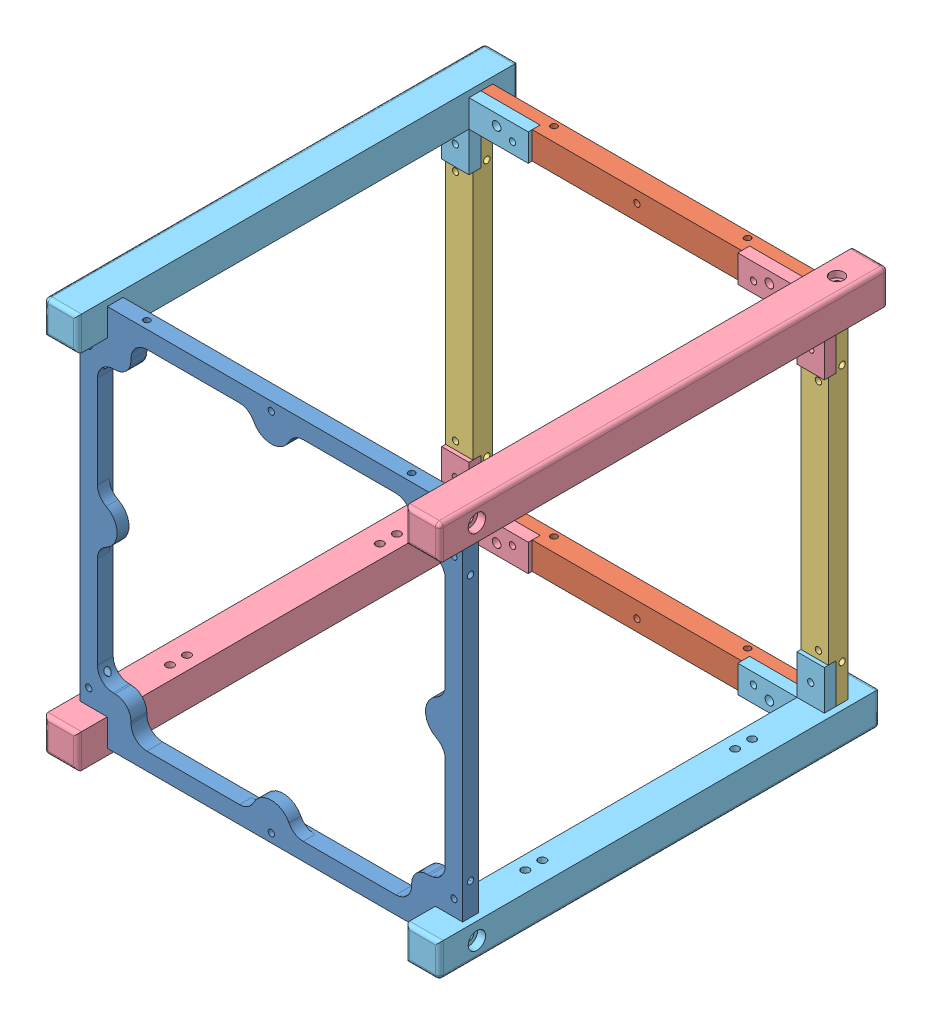
SolidWorks assembly B3_main, configuration ﾃﾞﾌｫﾙﾄ. Lengths in mm.
Overall size (100 100 113.5).
11 component instances, 6 part files, 32 mates.
Components (placement in the parent):
- B3_flame1-1: B3_flame1 [Default] at origin size (96.8 96.8 4)
- B3_flame2-1: B3_flame2 [Default] at (76.5 -8.5 -87.5) x (-1 0 0) z (0 1 0) size (83 5 6.9)
- B3_flame3-1: B3_flame3 [Default] at (100 -8.5 -85.4016) x (-1 0 0) z (0 1 0) size (6.9 5 83)
- B3_flame5-1: B3_flame5 [Default] at (100 -8.5 11.5) x (-1 0 0) z (0 1 0) size (23.5 113.5 18.5)
- B3_flame6-1: B3_flame6 [Default] at (91.5 -91.5 11.5) x (1 0 0) z (0 -1 0) size (23.5 111.5 18.5)
- B3_flame5-2: B3_flame5 [Default] at (0 -91.5 11.5) x (1 0 0) z (0 -1 0) size (23.5 113.5 18.5)
- B3_flame6-2: B3_flame6 [Default] at (8.5 -8.5 11.5) x (-1 0 0) z (0 1 0) size (23.5 111.5 18.5)
- B3_flame2-2: B3_flame2 [Default] at (23.5 -91.5 -87.5) x (1 0 0) z (0 -1 0) size (83 5 6.9)
- B3_flame3-2: B3_flame3 [Default] at (0 -91.5 -85.4016) x (1 0 0) z (0 -1 0) size (6.9 5 83)
- B3_flame7-1: B3_flame7 [Default] at (4.25 -91.5 -96.25) x (1 0 0) z (0 -1 0) size (5.5 8.5 5)
- B3_flame7-2: B3_flame7 [Default] at (95.75 -8.5 -96.25) x (-1 0 0) z (0 1 0) size (5.5 8.5 5)
Mates (geometry in assembly coordinates):
- Concentric5: concentric anti-aligned: cylinder of B3_flame3-1 through (94.95 -86.5 -93.5) axis (0 0 -1) radius 1.2; cylinder of B3_flame6-1 through (94.95 -86.5 -87.5) axis (0 0 1) radius 0.8
- Concentric6: concentric anti-aligned: cylinder of B3_flame3-1 through (94.95 -13.5 -93.5) axis (0 0 -1) radius 1.2; cylinder of B3_flame5-1 through (94.95 -13.5 -87.5) axis (0 0 1) radius 0.8
- Concentric7: concentric anti-aligned: cylinder of B3_flame6-2 through (5.05 -13.5 -87.5) axis (0 0 1) radius 0.8; cylinder of B3_flame3-2 through (5.05 -13.5 -93.5) axis (0 0 -1) radius 1.2
- Concentric9: concentric anti-aligned: cylinder of B3_flame2-1 through (15.5 -4.3 -93.5) axis (0 0 -1) radius 0.8; cylinder of B3_flame6-2 through (15.5 -4.3 -87.5) axis (0 0 1) radius 1.1
- Concentric10: concentric anti-aligned: cylinder of B3_flame2-1 through (84.5 -4.3 -93.5) axis (0 0 -1) radius 0.8; cylinder of B3_flame5-1 through (84.5 -4.3 -87.5) axis (0 0 1) radius 1.1
- Concentric11: concentric anti-aligned: cylinder of B3_flame5-2 through (15.5 -95.7 -87.5) axis (0 0 1) radius 1.1; cylinder of B3_flame2-2 through (15.5 -95.7 -93.5) axis (0 0 -1) radius 0.8
- Coincident1: coincident anti-aligned: plane of B3_flame2-1 through (91.5 0 -90.5) normal (0 0 1); plane of B3_flame5-1 through (76.5 0 -90.5) normal (0 0 -1)
- Coincident2: coincident anti-aligned: plane of B3_flame6-2 through (8.5 -18.5 -90.5) normal (0 0 -1); plane of B3_flame3-2 through (-1.5 -8.5 -90.5) normal (0 0 1)
- Coincident6: coincident aligned: plane of B3_flame6-2 through (1.6 -8.5 -97.5) normal (-1 0 0); plane of B3_flame3-2 through (1.6 -8.5 -83.5) normal (-1 0 0)
- Coincident7: coincident aligned: plane of B3_flame2-1 through (8.5 -1.6 -83.5) normal (0 1 0); plane of B3_flame6-2 through (23.5 -1.6 -97.5) normal (0 1 0)
- Coincident11: coincident anti-aligned: plane of B3_flame5-2 through (23.5 -100 -90.5) normal (0 0 -1); plane of B3_flame2-2 through (8.5 -100 -90.5) normal (0 0 1)
- Coincident12: coincident aligned: plane of B3_flame5-2 through (8.5 -98.4 -97.5) normal (0 -1 0); plane of B3_flame2-2 through (91.5 -98.4 -83.5) normal (0 -1 0)
- Coincident18: coincident anti-aligned: plane of B3_flame2-1 through (23.5 0 -90.5) normal (0 0 1); plane of B3_flame6-2 through (23.5 -8.5 -90.5) normal (0 0 -1)
- Concentric14: concentric anti-aligned: cylinder of B3_flame5-2 through (5.05 -86.5 -87.5) axis (0 0 1) radius 0.8; cylinder of B3_flame3-2 through (5.05 -86.5 -93.5) axis (0 0 -1) radius 1.2
- Coincident19: coincident anti-aligned: plane of B3_flame5-2 through (8.5 -81.5 -90.5) normal (0 0 -1); plane of B3_flame3-2 through (0 -91.5 -90.5) normal (0 0 1)
- Concentric15: concentric anti-aligned: cylinder of B3_flame6-1 through (84.5 -95.7 -87.5) axis (0 0 1) radius 1.1; cylinder of B3_flame2-2 through (84.5 -95.7 -93.5) axis (0 0 -1) radius 0.8
- Coincident20: coincident anti-aligned: plane of B3_flame6-1 through (76.5 -91.5 -90.5) normal (0 0 -1); plane of B3_flame2-2 through (76.5 -100 -90.5) normal (0 0 1)
- Coincident24: coincident anti-aligned: plane of B3_flame3-1 through (100 -8.5 -90.5) normal (0 0 1); plane of B3_flame5-1 through (91.5 -18.5 -90.5) normal (0 0 -1)
- Coincident26: coincident anti-aligned: plane of B3_flame3-1 through (91.5 -8.5 -87.5) normal (0 1 0); plane of B3_flame5-1 through (100 -8.5 11.5) normal (0 -1 0)
- Coincident27: coincident aligned: plane of B3_flame2-1 through (8.5 -1.6 -83.5) normal (0 1 0); plane of B3_flame5-1 through (91.5 -1.6 -97.5) normal (0 1 0)
- Coincident28: coincident anti-aligned: plane of B3_flame3-1 through (91.5 -91.5 -87.5) normal (0 -1 0); plane of B3_flame6-1 through (91.5 -91.5 11.5) normal (0 1 0)
- Coincident29: coincident aligned: plane of B3_flame6-1 through (76.5 -98.4 -97.5) normal (0 -1 0); plane of B3_flame2-2 through (91.5 -98.4 -83.5) normal (0 -1 0)
- Concentric16: concentric aligned: cylinder of B3_flame1-1 through (91.5 -95.75 2) axis (1 0 0) radius 0.8; cylinder of B3_flame6-1 through (100 -95.75 2) axis (1 0 0) radius 1.2
- Concentric17: concentric aligned: cylinder of B3_flame1-1 through (8.5 -95.75 2) axis (-1 0 0) radius 0.8; cylinder of B3_flame5-2 through (0 -95.75 2) axis (-1 0 0) radius 1.2
- Concentric18: concentric aligned: cylinder of B3_flame1-1 through (91.5 -4.25 2) axis (1 0 0) radius 0.8; cylinder of B3_flame5-1 through (100 -4.25 2) axis (1 0 0) radius 1.2
- Coincident30: coincident anti-aligned: plane of B3_flame1-1 through (8.5 0 4) normal (-1 0 0); plane of B3_flame6-2 through (8.5 0 11.5) normal (1 0 0)
- Coincident228: coincident anti-aligned: plane of B3_flame5-2 through (7 -96.5 -100.5) normal (0 0 1); plane of B3_flame7-1 through (1.5 -94.5 -100.5) normal (0 0 -1)
- Coincident229: coincident anti-aligned: plane of B3_flame5-2 through (0 -96.5 11.5) normal (0 1 0); plane of B3_flame7-1 through (4.25 -96.5 -96.25) normal (0 -1 0)
- Coincident230: coincident anti-aligned: plane of B3_flame5-1 through (93 -3.5 -100.5) normal (0 0 1); plane of B3_flame7-2 through (98.5 -5.5 -100.5) normal (0 0 -1)
- Coincident231: coincident anti-aligned: plane of B3_flame5-1 through (100 -3.5 11.5) normal (0 -1 0); plane of B3_flame7-2 through (95.75 -3.5 -96.25) normal (0 1 0)
- Concentric36: concentric aligned: cylinder of B3_flame5-1 through (95.75 0 -93.35) axis (0 1 0) radius 0.9; cylinder of B3_flame7-2 through (95.75 -3.5 -93.35) axis (0 1 0) radius 0.625
- Concentric37: concentric aligned: cylinder of B3_flame5-2 through (4.25 -100 -93.35) axis (0 -1 0) radius 0.9; cylinder of B3_flame7-1 through (4.25 -96.5 -93.35) axis (0 -1 0) radius 0.625
